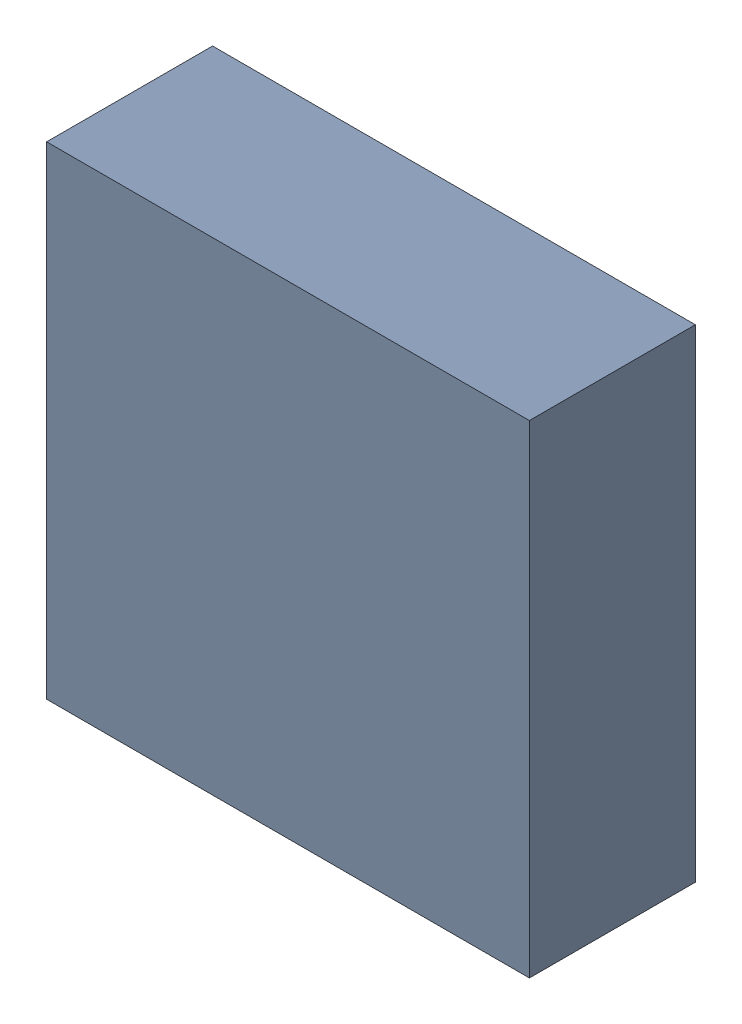
SolidWorks assembly U303_2PCB, configuration Default. Lengths in mm.
Overall size (3.2 3.2 1.1).
2 component instances, 1 part files, 0 mates.
Components (placement in the parent):
- 846484240-1: 846484240 [Default] at (141.1 100 0) size (3.2 3.2 1.1)
  - Extruded_11-1: Extruded_11 [Default] at origin size (3.2 3.2 1.1)
